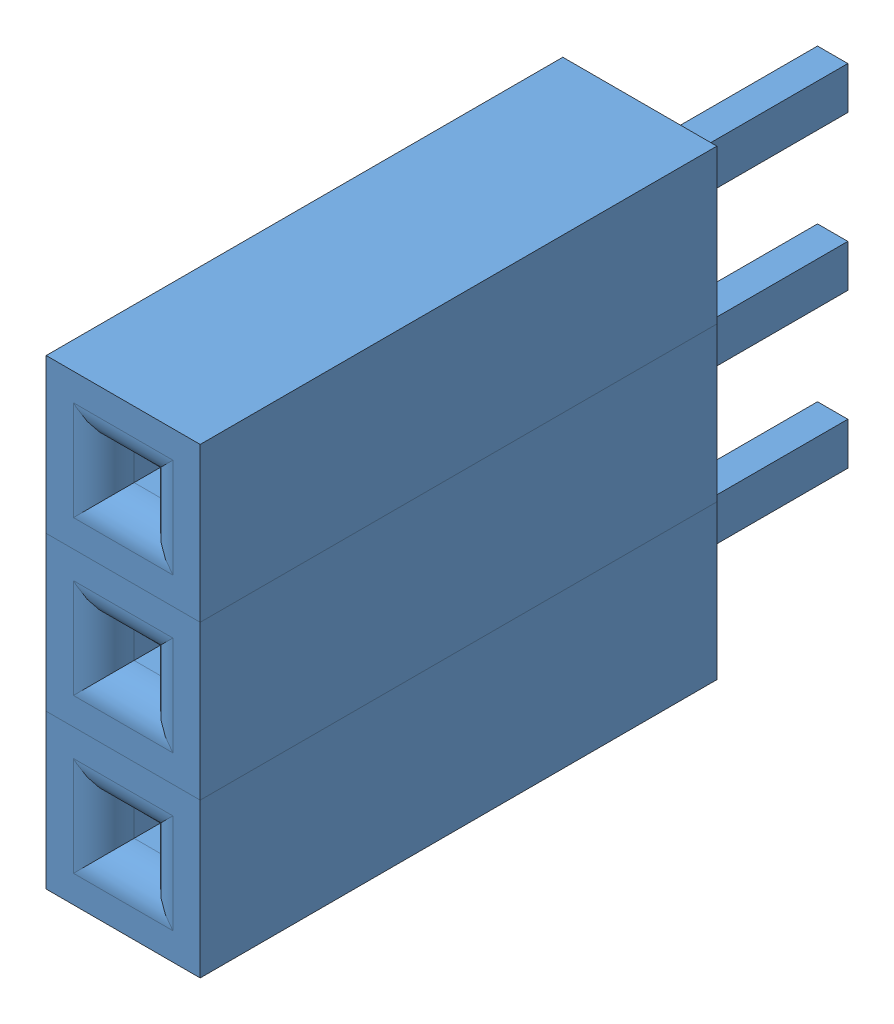
SolidWorks assembly Female Header 3 Pin, configuration Default. Lengths in mm.
Overall size (2.54 7.62 11.8).
3 component instances, 1 part files, 0 mates.
Components (placement in the parent):
- Female Header Pin-1: Female Header Pin [Default] at (-73.155 3.043 33.8655) size (2.54 2.54 11.8)
- Female Header Pin-2: Female Header Pin [Default] at (-73.155 5.583 33.8655) size (2.54 2.54 11.8)
- Female Header Pin-3: Female Header Pin [Default] at (-73.155 8.123 33.8655) size (2.54 2.54 11.8)
